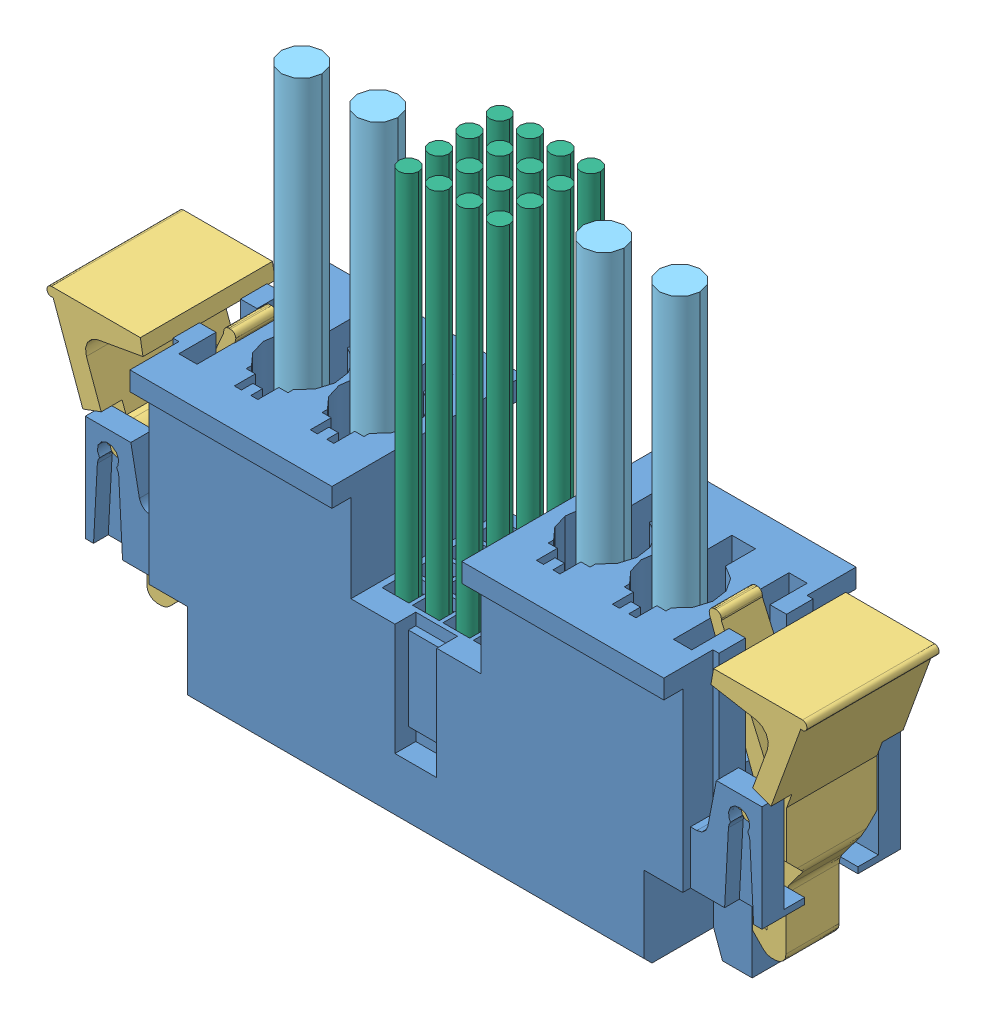
SolidWorks assembly MPCC-2-16-2-L-46-80-00-S, configuration Default. Lengths in mm.
Overall size (50.05 37.93 12.66).
24 component instances, 10 part files, 3 mates.
Components (placement in the parent):
- MPTC-02-16-02-6.30-01-L-V-LC-1: MPTC-02-16-02-6.30-01-L-V-LC [Default] at origin size (39.44 14.43 12.45) (suppressed, hidden)
  - MPTC_02_16_02_6_30_01_L_V_LC-1: MPTC_02_16_02_6_30_01_L_V_LC [Default] at (0 5.69 0) x (1 0 0) z (0 1 0) size (39.44 12.45 14.43)
    - _MPTC_02_16_02_6_30_V_LC_t_2-1: _MPTC_02_16_02_6_30_V_LC_t_2 [Default] at origin size (39.44 12.45 11.38)
    - _MPTC_02_16_02_6_30_01_V_p_4-1: _MPTC_02_16_02_6_30_01_V_p_4 [Default] at (0 0.0048 0.532) size (6.5 6.5 13.69)
    - _MPTC_01_04_01_6_30_01_L_V_c_6-1: _MPTC_01_04_01_6_30_01_L_V_c_6 [Default] at (16.255 -2.145 -4.76) x (0 1 0) z (1 0 0) size (1.42 4.7 0.25)
    - _MPTC_01_04_01_6_30_01_L_V_c_6-2: _MPTC_01_04_01_6_30_01_L_V_c_6 [Default] at (-16.255 -2.145 -4.76) x (0 1 0) z (1 0 0) size (1.42 4.7 0.25)
    - _MPTC_01_V_pp_9-1: _MPTC_01_V_pp_9 [Default] at (12.445 -2.605 -1.744) x (0 0 1) z (-1 0 0) size (13.75 7.62 2.29)
    - _MPTC_01_V_pp_9-2: _MPTC_01_V_pp_9 [Default] at (-12.445 -2.605 -1.744) x (0 0 1) z (-1 0 0) size (13.75 7.62 2.29)
    - _MPTC_01_V_pp_9-3: _MPTC_01_V_pp_9 [Default] at (7.445 -2.605 -1.744) x (0 0 1) z (-1 0 0) size (13.75 7.62 2.29)
    - _MPTC_01_V_pp_9-4: _MPTC_01_V_pp_9 [Default] at (-7.445 -2.605 -1.744) x (0 0 1) z (-1 0 0) size (13.75 7.62 2.29)
- MPCC_2_16_2_L_46_80_00_S-1: MPCC_2_16_2_L_46_80_00_S [Default] at (0 24.7 0) x (0 1 0) z (-1 0 0) size (37.93 12.66 50.05)
  - _MPC_2_16_2_C_body_2-1: _MPC_2_16_2_C_body_2 [Default] at (0 -6.33 0) x (0 0 1) z (-1 0 0) size (44.55 12.66 20.9)
  - _MPC_16__V_signal_pins_4-1: _MPC_16__V_signal_pins_4 [Default] at (-16.28 0 0) x (0 0 1) z (-1 0 0) size (7.32 6.5 10.38)
  - _LTC_22_6-1: _LTC_22_6 [Default] at (-7.3 0 20.775) x (0 -1 0) z (0 0 -1) size (8.7 17.64 9.44)
  - _LTC_22_6-2: _LTC_22_6 [Default] at (-7.3 0 -20.775) x (0 1 0) z (0 0 1) size (8.7 17.64 9.44)
  - _MPC_01_V_pp_9-1: _MPC_01_V_pp_9 [Default] at (-15.85 -2.54 -12.445) x (-1 0 0) z (0 0 -1) size (9.41 7.05 3)
  - _MPC_01_V_pp_9-2: _MPC_01_V_pp_9 [Default] at (-15.85 -2.54 -7.445) x (-1 0 0) z (0 0 -1) size (9.41 7.05 3)
  - _MPC_01_V_pp_9-3: _MPC_01_V_pp_9 [Default] at (-15.85 -2.54 7.445) x (-1 0 0) z (0 0 -1) size (9.41 7.05 3)
  - _MPC_01_V_pp_9-4: _MPC_01_V_pp_9 [Default] at (-15.85 -2.54 12.445) x (-1 0 0) z (0 0 -1) size (9.41 7.05 3)
  - _DWC_14_1_14-1: _DWC_14_1_14 [Default] at (-7.97 -0.15 12.445) x (0 0 1) z (-1 0 0) size (2.67 2.67 25)
  - _DWC_14_1_14-2: _DWC_14_1_14 [Default] at (-7.97 -0.15 7.445) x (0 0 1) z (-1 0 0) size (2.67 2.67 25)
  - _DWC_14_1_14-3: _DWC_14_1_14 [Default] at (-7.97 -0.15 -7.445) x (0 0 1) z (-1 0 0) size (2.67 2.67 25)
  - _DWC_14_1_14-4: _DWC_14_1_14 [Default] at (-7.97 -0.15 -12.445) x (0 0 1) z (-1 0 0) size (2.67 2.67 25)
  - _DWC_26_16_19-1: _DWC_26_16_19 [Default] at (-8.97 -2.555 0) x (0 0 1) z (-1 0 0) size (8 8 26)
Mates (geometry in assembly coordinates):
- Width1: width: plane of MPTC-02-16-02-6.30-01-L-V-LC-1/MPTC_02_16_02_6_30_01_L_V_LC-1/_MPTC_02_16_02_6_30_V_LC_t_2-1 through (15.291 6.3 -5.336) normal (0 0 1); plane of MPTC-02-16-02-6.30-01-L-V-LC-1/MPTC_02_16_02_6_30_01_L_V_LC-1/_MPTC_02_16_02_6_30_V_LC_t_2-1 through (-15.291 6.3 5.336) normal (0 0 -1); plane of MPCC_2_16_2_L_46_80_00_S-1/_MPC_2_16_2_C_body_2-1 through (-17.575 23.45 -5.08) normal (0 0 -1); plane of MPCC_2_16_2_L_46_80_00_S-1/_MPC_2_16_2_C_body_2-1 through (17.575 23.45 5.08) normal (0 0 1)
- Width2: width: plane of MPCC_2_16_2_L_46_80_00_S-1/_MPC_2_16_2_C_body_2-1 through (-17.575 15.015 6.33) normal (-1 0 0); plane of MPCC_2_16_2_L_46_80_00_S-1/_MPC_2_16_2_C_body_2-1 through (17.575 15.015 -6.33) normal (1 0 0); plane of MPTC-02-16-02-6.30-01-L-V-LC-1/MPTC_02_16_02_6_30_01_L_V_LC-1/_MPTC_02_16_02_6_30_V_LC_t_2-1 through (-17.831 11.38 -4.824) normal (1 0 0); plane of MPTC-02-16-02-6.30-01-L-V-LC-1/MPTC_02_16_02_6_30_01_L_V_LC-1/_MPTC_02_16_02_6_30_V_LC_t_2-1 through (17.831 11.38 0.764) normal (-1 0 0)
- Coincident1: coincident: plane of MPTC-02-16-02-6.30-01-L-V-LC-1/MPTC_02_16_02_6_30_01_L_V_LC-1/_MPTC_02_16_02_6_30_V_LC_t_2-1 through (0 6.3 0) normal (0 1 0); plane of MPCC_2_16_2_L_46_80_00_S-1/_MPC_2_16_2_C_body_2-1 through (15.035 6.3 -6.33) normal (0 -1 0)
